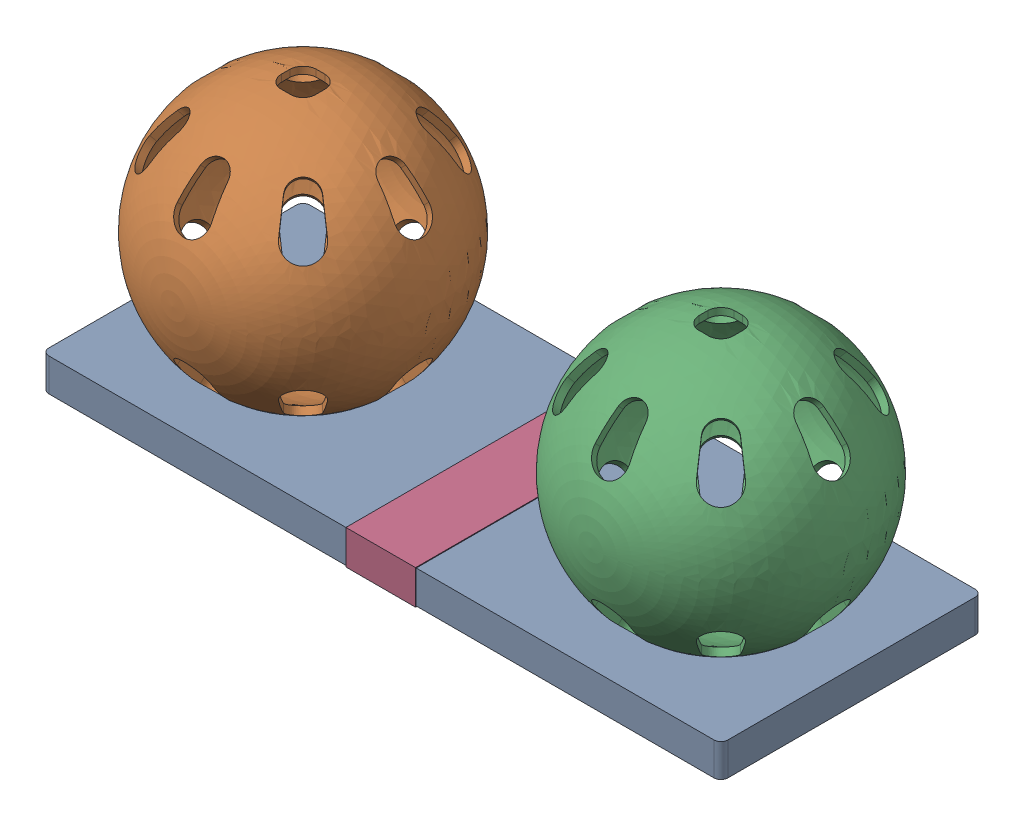
SolidWorks assembly FIELD_RelicRecovery_Low Ball Holder-, configuration Default. Lengths in mm.
Overall size (247.65 98.04 95.76).
4 component instances, 3 part files, 0 mates.
Components (placement in the parent):
- FIELD_RelicRecovery_LBH Base-1: FIELD_RelicRecovery_LBH Base [Default] at origin size (247.65 12 95.25)
- FIELD_RelicRecovery_am-3364R am-3364B Particle-1: FIELD_RelicRecovery_am-3364R am-3364B Particle [Default] at (-76.2 50.165 0) x (1 0 0) z (0 1 0) size (95.25 95.25 95.25)
- FIELD_RelicRecovery_am-3364R am-3364B Particle-2: FIELD_RelicRecovery_am-3364R am-3364B Particle [Default] at (76.2 50.165 0) x (1 0 0) z (0 1 0) size (95.25 95.25 95.25)
- FIELD_RelicRecovery_LBH Tape-1: FIELD_RelicRecovery_LBH Tape [Default] at (0 6 0) size (25.4 12.51 95.76)
